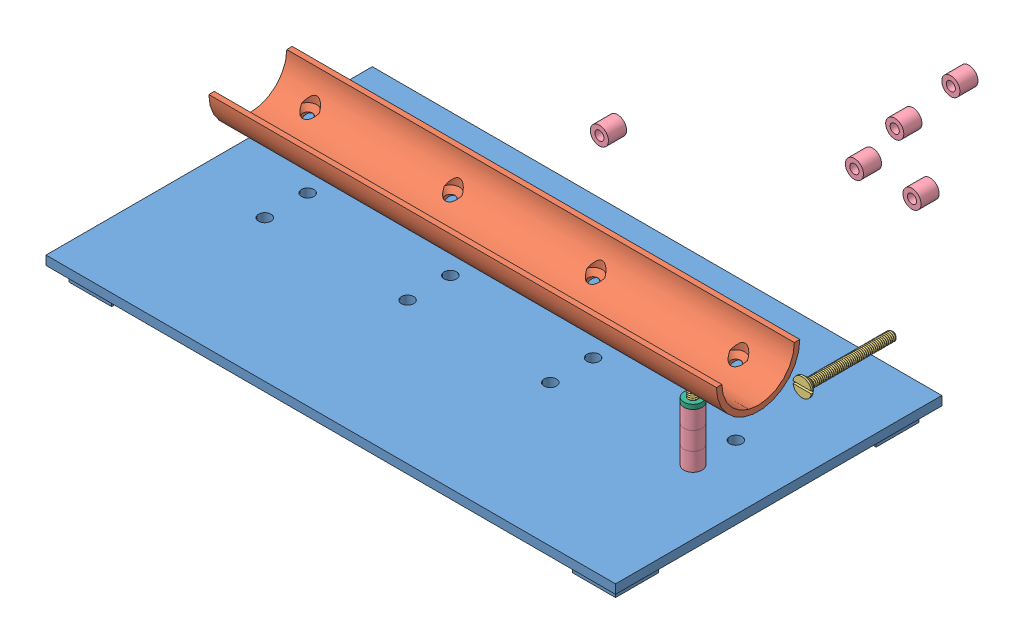
SolidWorks assembly extension assembly, configuration Default. Lengths in mm.
Overall size (412.05 213.94 271.16).
14 component instances, 6 part files, 15 mates.
Components (placement in the parent):
- horizontal jig plate long-1: horizontal jig plate long [Default] at (-253.5306 12.9767 -93.7422) size (399 16.35 228.6)
- antenna holder-1: antenna holder [Default] at (-224.5306 82.3187 20.5578) x (0 0 -1) z (-1 0 0) size (58.42 29.21 355.6)
- 2halfinchnylonscrew-1: 2halfinchnylonscrew [94605A360] at (100.4694 60.7054 35.5578) x (-0.618929 0 0.785447) z (0 1 0) size (12.78 12.88 64.24)
- 2halfinchnylonscrew-2: 2halfinchnylonscrew [94605A360] at (132.4469 53.8102 -12.8172) size (12.78 12.88 64.24)
- halfinchnylonspacer-1: halfinchnylonspacer [94639A503] at (100.4694 19.3267 35.5578) x (1 0 0) z (0 -1 0) size (12.7 12.7 12.7)
- nylonhexnut-1: nylonhexnut [94812A116] at (100.6711 3.2692 35.5232) size (11.11 6.94 12.83)
- smallnylonspacer-1: smallnylonspacer [94639A567] at (100.4694 52.6642 35.5578) x (1 0 0) z (0 -1 0) size (12.7 12.7 3.17)
- halfinchnylonspacer-2: halfinchnylonspacer [94639A503] at (100.4694 44.7267 35.5578) x (1 0 0) z (0 -1 0) size (12.7 12.7 12.7)
- halfinchnylonspacer-3: halfinchnylonspacer [94639A503] at (-17.4658 127.6938 -23.1096) size (12.7 12.7 12.7)
- halfinchnylonspacer-4: halfinchnylonspacer [94639A503] at (100.4694 32.0267 35.5578) x (1 0 0) z (0 -1 0) size (12.7 12.7 12.7)
- halfinchnylonspacer-5: halfinchnylonspacer [94639A503] at (135.5066 171.0913 -48.8033) size (12.7 12.7 12.7)
- halfinchnylonspacer-6: halfinchnylonspacer [94639A503] at (148.4629 145.7655 -76.1832) size (12.7 12.7 12.7)
- halfinchnylonspacer-7: halfinchnylonspacer [94639A503] at (82.6239 128.5357 -129.9535) size (12.7 12.7 12.7)
- halfinchnylonspacer-8: halfinchnylonspacer [94639A503] at (152.1732 204.2169 -99.691) size (12.7 12.7 12.7)
Mates (geometry in assembly coordinates):
- Parallel1: parallel: plane of horizontal jig plate long-1 through (-253.5306 12.9767 -93.7422) normal (0 1 0); plane of antenna holder-1 through (-224.5306 82.3187 20.5578) normal (0 1 0)
- Distance1: distance = 43.942 mm: cylinder of antenna holder-1 through (131.0694 82.3187 20.5578) axis (-1 0 0) radius 25.4; plane of horizontal jig plate long-1 through (-253.5306 12.9767 -93.7422) normal (0 1 0)
- Parallel2: parallel: plane of horizontal jig plate long-1 through (-253.5306 12.9767 -93.7422) normal (0 1 0); plane of antenna holder-1 through (-224.5306 82.3187 20.5578) normal (0 1 0)
- Concentric7: concentric: circle of horizontal jig plate long-1; circle of antenna holder-1
- Concentric8: concentric: cylinder of horizontal jig plate long-1 through (-199.5306 12.9767 5.5578) axis (0 1 0) radius 4.3688; cylinder of antenna holder-1 through (-199.5306 82.3187 5.5578) axis (0 1 0) radius 3.3782
- Coincident1: coincident: cone of antenna holder-1 through (100.4694 63.3187 35.5578) axis (0 -1 0); cone of 2halfinchnylonscrew-1 through (100.4694 63.3187 35.5578) axis (0 -1 0)
- Coincident2: coincident: plane of horizontal jig plate long-1 through (-253.5306 12.9767 -93.7422) normal (0 1 0); plane of halfinchnylonspacer-1 through (100.4694 12.9767 35.5578) normal (0 -1 0)
- Concentric9: concentric: cylinder of horizontal jig plate long-1 through (100.4694 12.9767 35.5578) axis (0 1 0) radius 4.3688; cylinder of halfinchnylonspacer-1 through (100.4694 12.9767 35.5578) axis (0 1 0) radius 3.2004
- Coincident3: coincident: plane of halfinchnylonspacer-1 through (100.4694 25.6767 35.5578) normal (0 1 0); plane of halfinchnylonspacer-4 through (100.4694 25.6767 35.5578) normal (0 -1 0)
- Concentric10: concentric: cylinder of halfinchnylonspacer-1 through (100.4694 12.9767 35.5578) axis (0 1 0) radius 3.2004; cylinder of halfinchnylonspacer-4 through (100.4694 25.6767 35.5578) axis (0 1 0) radius 3.2004
- Coincident4: coincident: plane of halfinchnylonspacer-2 through (100.4694 38.3767 35.5578) normal (0 -1 0); plane of halfinchnylonspacer-4 through (100.4694 38.3767 35.5578) normal (0 1 0)
- Concentric11: concentric: cylinder of halfinchnylonspacer-2 through (100.4694 38.3767 35.5578) axis (0 1 0) radius 3.2004; cylinder of halfinchnylonspacer-4 through (100.4694 25.6767 35.5578) axis (0 1 0) radius 3.2004
- Coincident5: coincident: plane of smallnylonspacer-1 through (100.4694 51.0767 35.5578) normal (0 -1 0); plane of halfinchnylonspacer-2 through (100.4694 51.0767 35.5578) normal (0 1 0)
- Concentric12: concentric: cylinder of smallnylonspacer-1 through (100.4694 51.0767 35.5578) axis (0 1 0) radius 3.2004; cylinder of halfinchnylonspacer-2 through (100.4694 38.3767 35.5578) axis (0 1 0) radius 3.2004
- Coincident6: coincident: plane of horizontal jig plate long-1 through (-253.5306 6.6267 -93.7422) normal (0 -1 0); plane of nylonhexnut-1 through (100.6711 6.6267 35.5232) normal (0 1 0)
